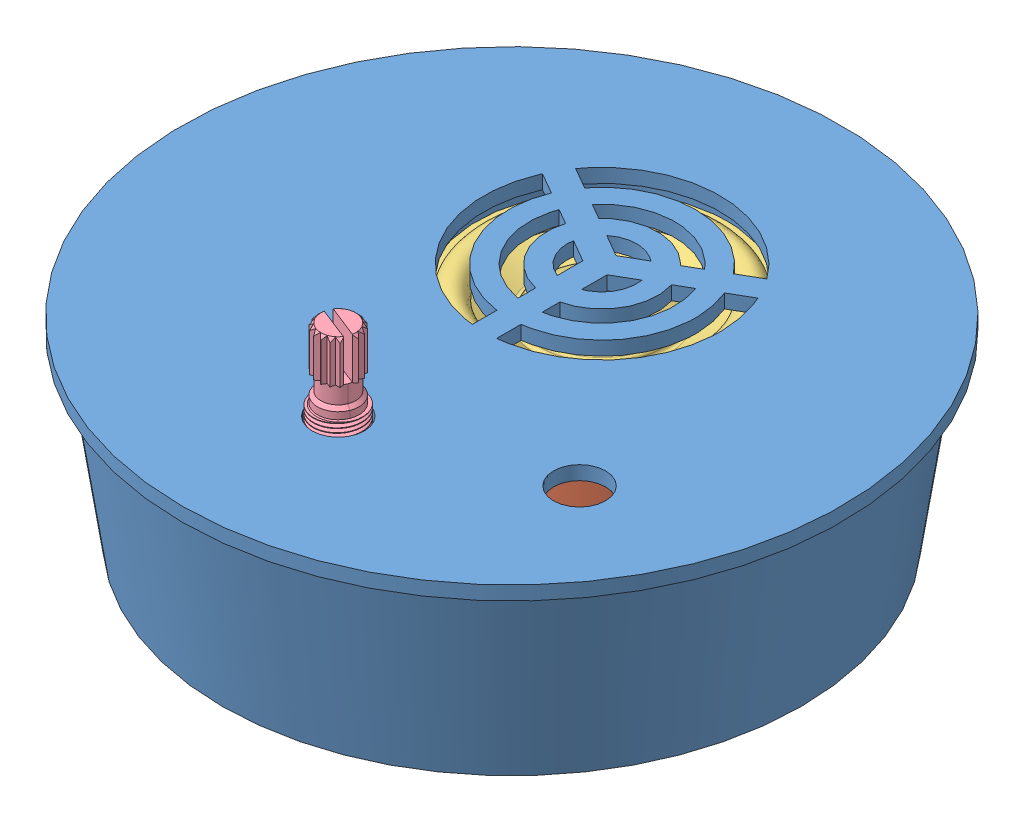
SolidWorks assembly QuickAndDirtyAssy, configuration Default. Lengths in mm.
Overall size (95 39.54 100.18).
4 component instances, 4 part files, 5 mates.
Components (placement in the parent):
- cap-for-cup-v2-1: cap-for-cup-v2 [Default] at (-67.0034 56.5757 0) size (95 27.91 95)
- speaker-retainer-ring-1: speaker-retainer-ring [Default] at (-67.0033 35.5757 -13) x (0.500006 0 -0.866022) z (-0.866022 0 -0.500006) size (56.99 8.8 51.3)
- Speaker AS04004PR-R-1: Speaker AS04004PR-R [Default] at (-67.0033 54.0104 -13) x (0.940903 0 -0.338676) z (-0.338676 0 -0.940903) size (40.01 17.61 40.01)
- Volume Pot On Off ptr901-2x15k-xxxx-1: Volume Pot On Off ptr901-2x15k-xxxx [Default] at (-67.0034 46.1684 25) x (0 1 0) z (0.930454 0 0.366408) size (28.4 14.85 9.6)
Mates (geometry in assembly coordinates):
- Coincident2: coincident anti-aligned: plane of cap-for-cup-v2-1 through (-67.0034 35.5757 -13) normal (0 -1 0); plane of speaker-retainer-ring-1 through (-87.0035 35.5757 21.6409) normal (0 1 0)
- Concentric1: concentric anti-aligned: cylinder of cap-for-cup-v2-1 through (-67.0034 35.5757 10.75) axis (0 -1 0) radius 1.9; cylinder of speaker-retainer-ring-1 through (-67.0034 35.5757 10.75) axis (0 1 0) radius 2.6
- Concentric2: concentric anti-aligned: cylinder of cap-for-cup-v2-1 through (-46.4352 35.5757 -24.8747) axis (0 -1 0) radius 1.9; cylinder of speaker-retainer-ring-1 through (-46.4351 35.5757 -24.8749) axis (0 1 0) radius 2.6
- Concentric3: concentric anti-aligned: cylinder of speaker-retainer-ring-1 through (-67.0033 5.4986 -13) axis (0 -1 0) radius 12; cylinder of Speaker AS04004PR-R-1 through (-67.0033 40.6104 -13) axis (0 1 0) radius 11.5
- Concentric4: concentric aligned: cylinder of cap-for-cup-v2-1 through (-67.0034 28.6739 25) axis (0 1 0) radius 3.75; cylinder of Volume Pot On Off ptr901-2x15k-xxxx-1 through (-67.0034 58.2184 25) axis (0 1 0) radius 3
